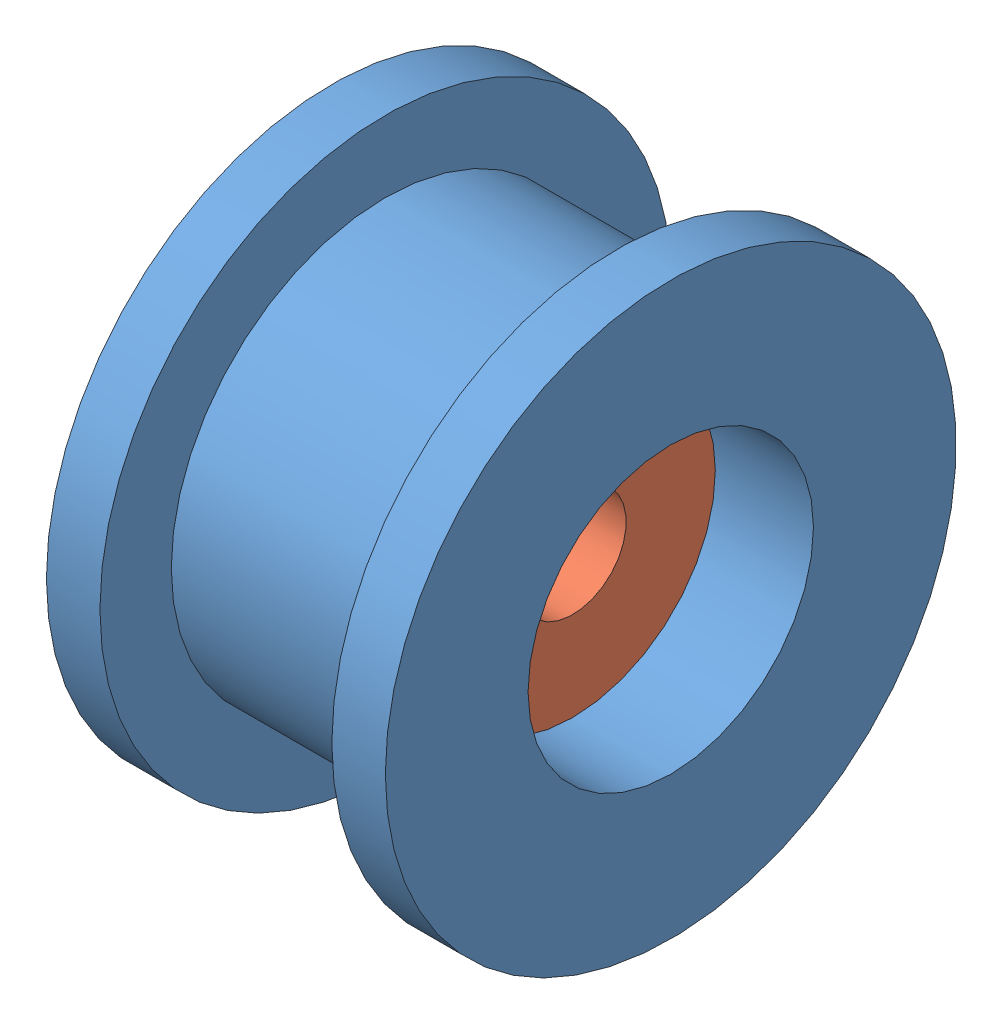
SolidWorks assembly ASM_poulie_roue_libre, configuration Défaut. Lengths in mm.
Overall size (9.5 16 16).
2 component instances, 2 part files, 2 mates.
Components (placement in the parent):
- Poulie1_623zz-1: Poulie1_623zz [Défaut] at (1.4245 0.9314 16) size (9.5 16 16)
- 623ZZ-1: 623ZZ [Défaut] at (-1.3255 0.9314 16) x (0 0 -1) z (1 0 0) size (10 10 4)
Mates (geometry in assembly coordinates):
- Coïncidente1: coincident anti-aligned: plane of Poulie1_623zz-1 through (2.6745 4.9314 16) normal (-1 0 0); plane of 623ZZ-1 through (2.6745 0.9314 16) normal (1 0 0)
- Coaxiale1: concentric aligned: cylinder of Poulie1_623zz-1 through (-15.879 0.9314 16) axis (-1 0 0) radius 4.975; cylinder of 623ZZ-1 through (2.6745 0.9314 16) axis (-1 0 0) radius 5
